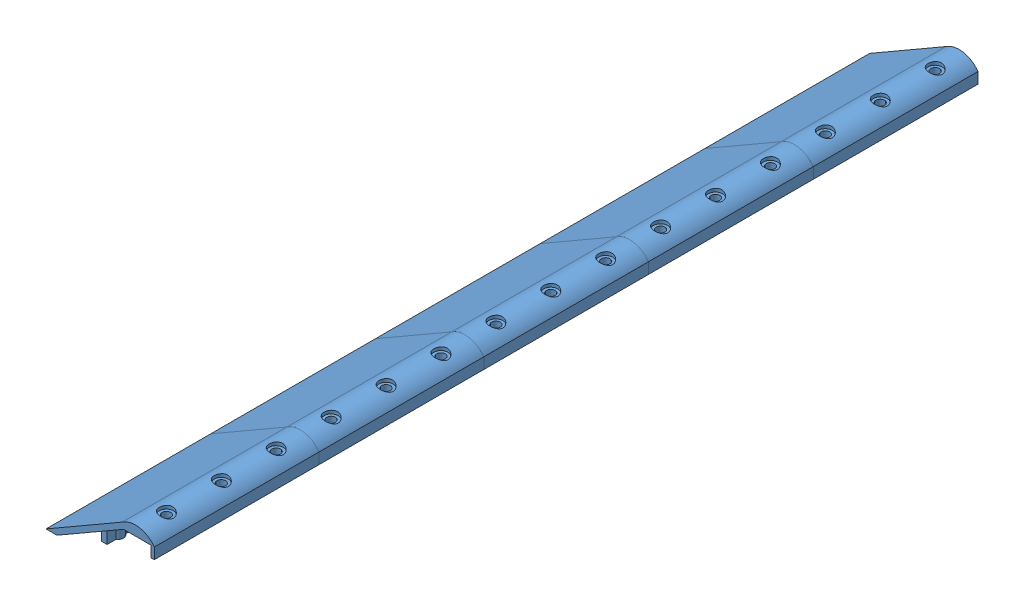
SolidWorks assembly PALAS UNIDAS, configuration Predeterminado. Lengths in mm.
Overall size (98.62 43.88 750).
5 component instances, 1 part files, 12 mates.
Components (placement in the parent):
- pala2-2: pala2 [Predeterminado] at (-21.0812 39.4806 175.798) size (98.62 43.88 150)
- pala2-4: pala2 [Predeterminado] at (-21.0812 39.4806 325.798) size (98.62 43.88 150)
- pala2-5: pala2 [Predeterminado] at (-21.0812 39.4806 475.798) size (98.62 43.88 150)
- pala2-6: pala2 [Predeterminado] at (-21.0812 39.4806 625.798) size (98.62 43.88 150)
- pala2-7: pala2 [Predeterminado] at (-21.0812 39.4806 25.798) size (98.62 43.88 150)
Mates (geometry in assembly coordinates):
- Coincidente7: coincident: plane of pala2-2 through (-21.0812 39.4806 100.798) normal (0 0 -1); plane of pala2-7 through (-21.0812 39.4806 100.798) normal (0 0 1)
- Coincidente8: coincident: plane of pala2-2 through (6.9188 39.4806 250.798) normal (1 0 0); plane of pala2-7 through (6.9188 39.4806 100.798) normal (1 0 0)
- Coincidente9: coincident: plane of pala2-2 through (-21.0812 39.4806 250.798) normal (0 -1 0); plane of pala2-7 through (-21.0812 39.4806 100.798) normal (0 -1 0)
- Coincidente11: coincident: plane of pala2-2 through (-21.0812 39.4806 250.798) normal (0 0 1); plane of pala2-4 through (-21.0812 39.4806 250.798) normal (0 0 -1)
- Coincidente12: coincident: plane of pala2-2 through (6.9188 39.4806 250.798) normal (1 0 0); plane of pala2-4 through (6.9188 39.4806 400.798) normal (1 0 0)
- Coincidente13: coincident: plane of pala2-4 through (-21.0812 39.4806 400.798) normal (0 0 1); plane of pala2-5 through (-21.0812 39.4806 400.798) normal (0 0 -1)
- Coincidente14: coincident: plane of pala2-5 through (-21.0812 39.4806 550.798) normal (0 0 1); plane of pala2-6 through (-21.0812 2.3711 550.798) normal (0 0 -1)
- Coincidente15: coincident: plane of pala2-6 through (6.9188 2.3711 700.798) normal (1 0 0); plane of pala2-5 through (6.9188 39.4806 550.798) normal (1 0 0)
- Coincidente16: coincident: plane of pala2-2 through (6.9188 39.4806 250.798) normal (1 0 0); plane of pala2-4 through (6.9188 39.4806 400.798) normal (1 0 0)
- Coincidente17: coincident: plane of pala2-2 through (-21.0812 39.4806 250.798) normal (0 -1 0); plane of pala2-4 through (-21.0812 39.4806 400.798) normal (0 -1 0)
- Coincidente18: coincident: plane of pala2-4 through (-21.0812 39.4806 400.798) normal (0 -1 0); plane of pala2-5 through (-21.0812 39.4806 550.798) normal (0 -1 0)
- Coincidente19: coincident: plane of pala2-5 through (-21.0812 39.4806 550.798) normal (0 -1 0); plane of pala2-6 through (-21.0812 39.4806 700.798) normal (0 -1 0)
